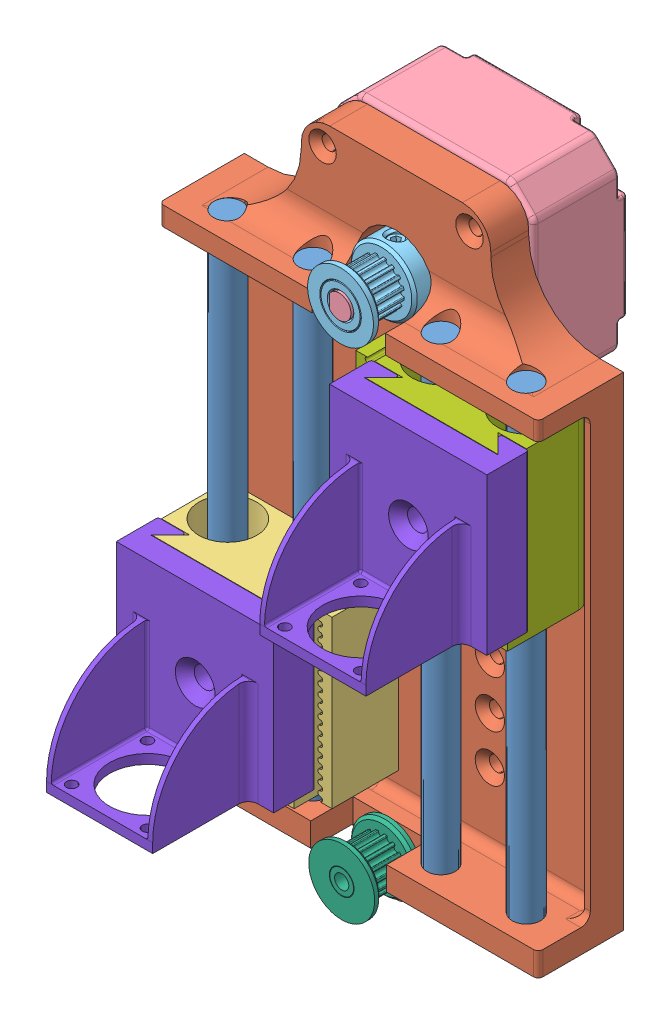
SolidWorks assembly Сборка1, configuration По умолчанию. Lengths in mm.
Overall size (80 136.39 68.13).
12 component instances, 8 part files, 26 mates.
Components (placement in the parent):
- 6x100-1: 6x100 [По умолчанию] at (56.1311 0.0146 -7.1072) x (1 0 0) z (0 1 0) size (6 6 100)
- main-1: main [По умолчанию] at (87.6311 49.0146 -19.1072) size (80 135.39 18)
- 6x100-2: 6x100 [По умолчанию] at (74.1311 0.0146 -7.1072) x (1 0 0) z (0 1 0) size (6 6 100)
- 6x100-3: 6x100 [По умолчанию] at (101.1311 0.0146 -7.1072) x (1 0 0) z (0 1 0) size (6 6 100)
- 6x100-4: 6x100 [По умолчанию] at (119.1311 0.0146 -7.1072) x (0.999887 0 -0.01506) z (0 1 0) size (6 6 100)
- head-1: head [По умолчанию] at (65.1311 25.9903 -14.1072) size (36 35 18)
- Short Body Nema 17 Bipolar Step Motor-1: Short Body Nema 17 Bipolar Step Motor [По умолчанию] at (66.6311 81.0146 -39.1072) size (42 42 40)
- GT2_16T-1: GT2_16T [Конфигурация1] at (87.6311 102.0146 -14.8955) x (0 0 1) z (-0.998524 -0.054321 0) size (15.5 13.9 13.9)
- GT2 16 Teeth Free Pulley-1: GT2 16 Teeth Free Pulley [По умолчанию] at (87.6311 -3.3706 -14.943) x (0 0 1) z (-0.999696 -0.02467 0) size (9.9 13.9 13.9)
- head2-1: head2 [По умолчанию] at (110.1311 77.2667 -14.1072) x (-1 0 0) z (0 0 1) size (36 35 18)
- nema8_holder-1: nema8_holder [По умолчанию] at (65.2175 10.4903 0.0436) x (1 0 0) z (0 1 0) size (33.2 29.03 33)
- nema8_holder-2: nema8_holder [По умолчанию] at (110.2175 61.7667 0.0436) x (1 0 0) z (0 1 0) size (33.2 29.03 33)
Mates (geometry in assembly coordinates):
- Концентричный4: concentric anti-aligned: cylinder of 6x100-1 through (56.1311 100.0146 -7.1072) axis (0 -1 0) radius 3; cylinder of main-1 through (56.1311 0.0146 -7.1072) axis (0 1 0) radius 2.95
- Совпадение1: coincident aligned: plane of 6x100-1 through (56.1311 100.0146 -7.1072) normal (0 1 0); plane of main-1 through (47.6311 100.0146 -15.1072) normal (0 1 0)
- Концентричный5: concentric anti-aligned: cylinder of main-1 through (74.1311 0.0146 -7.1072) axis (0 1 0) radius 2.95; cylinder of 6x100-2 through (74.1311 100.0146 -7.1072) axis (0 -1 0) radius 3
- Совпадение2: coincident aligned: plane of main-1 through (47.6311 100.0146 -15.1072) normal (0 1 0); plane of 6x100-2 through (74.1311 100.0146 -7.1072) normal (0 1 0)
- Концентричный6: concentric anti-aligned: cylinder of main-1 through (101.1311 0.0146 -7.1072) axis (0 1 0) radius 2.95; cylinder of 6x100-3 through (101.1311 100.0146 -7.1072) axis (0 -1 0) radius 3
- Совпадение3: coincident aligned: plane of main-1 through (47.6311 100.0146 -15.1072) normal (0 1 0); plane of 6x100-3 through (101.1311 100.0146 -7.1072) normal (0 1 0)
- Концентричный7: concentric anti-aligned: cylinder of main-1 through (119.1311 0.0146 -7.1072) axis (0 1 0) radius 2.95; cylinder of 6x100-4 through (119.1311 100.0146 -7.1072) axis (0 -1 0) radius 3
- Совпадение5: coincident anti-aligned: plane of main-1 through (119.1311 0.0146 -7.1072) normal (0 1 0); plane of 6x100-4 through (119.1311 0.0146 -7.1072) normal (0 -1 0)
- Концентричный8: concentric anti-aligned: cylinder of 6x100-1 through (56.1311 100.0146 -7.1072) axis (0 -1 0) radius 3; cylinder of head-1 through (56.1311 8.4893 -7.1072) axis (0 1 0) radius 6.1
- Параллельность1: parallel anti-aligned: cylinder of 6x100-2 through (74.1311 100.0146 -7.1072) axis (0 -1 0) radius 3; cylinder of head-1 through (74.1311 8.4893 -7.1072) axis (0 1 0) radius 6.1
- Концентричный10: concentric anti-aligned: cylinder of 6x100-2 through (74.1311 100.0146 -7.1072) axis (0 -1 0) radius 3; cylinder of head-1 through (74.1311 8.4893 -7.1072) axis (0 1 0) radius 6.1
- Концентричный11: concentric anti-aligned: cylinder of 6x100-3 through (101.1311 100.0146 -7.1072) axis (0 -1 0) radius 3; cylinder of head-2 through (101.1311 60.8768 -7.1072) axis (0 1 0) radius 6
- Концентричный12: concentric anti-aligned: cylinder of 6x100-4 through (119.1311 100.0146 -7.1072) axis (0 -1 0) radius 3; cylinder of head-2 through (119.1311 60.8768 -7.1072) axis (0 1 0) radius 6
- Концентричный13: concentric aligned: cylinder of main-1 through (87.6311 102.0146 -1.1062) axis (0 0 -1) radius 8; cylinder of Short Body Nema 17 Bipolar Step Motor-1 through (87.6311 102.0146 -19.1072) axis (0 0 -1) radius 11
- Концентричный14: concentric aligned: cylinder of main-1 through (103.1311 117.5146 -1.1062) axis (0 0 -1) radius 1.5; cylinder of Short Body Nema 17 Bipolar Step Motor-1 through (103.1311 117.5146 -20.3572) axis (0 0 -1) radius 1.23
- Совпадение6: coincident anti-aligned: plane of main-1 through (87.6311 49.0146 -19.1072) normal (0 0 -1); plane of Short Body Nema 17 Bipolar Step Motor-1 through (87.6311 102.0146 -19.1072) normal (0 0 1)
- Концентричный15: concentric anti-aligned: cylinder of Short Body Nema 17 Bipolar Step Motor-1 through (87.6311 102.0146 -19.1072) axis (0 0 -1) radius 2.5; cylinder of GT2_16T-1 through (87.6311 102.0146 -14.8955) axis (0 0 1) radius 2.5
- Концентричный17: concentric anti-aligned: cylinder of main-1 through (87.6311 -3.3706 -19.1082) axis (0 0 1) radius 1.5; cylinder of GT2 16 Teeth Free Pulley-1 through (87.6311 -3.3706 -9.543) axis (0 0 -1) radius 1.5
- Концентричный18: concentric aligned: cylinder of 6x100-3 through (101.1311 100.0146 -7.1072) axis (0 -1 0) radius 3; cylinder of head2-1 through (101.1311 94.7677 -7.1072) axis (0 -1 0) radius 6.1
- Концентричный19: concentric aligned: cylinder of 6x100-4 through (119.1311 100.0146 -7.1072) axis (0 -1 0) radius 3; cylinder of head2-1 through (119.1311 94.7677 -7.1072) axis (0 -1 0) radius 6.1
- Совпадение7: coincident anti-aligned: plane of head-1 through (79.1311 10.4903 3.8928) normal (0.707107 0 -0.707107); plane of nema8_holder-1 through (79.2311 43.4903 3.9928) normal (-0.707107 0 0.707107)
- Совпадение8: coincident anti-aligned: plane of head-1 through (51.1311 10.4903 3.8928) normal (-0.707107 0 -0.707107); plane of nema8_holder-1 through (51.0311 43.4903 3.9928) normal (0.707107 0 0.707107)
- Совпадение9: coincident aligned: plane of head-1 through (49.1311 43.4903 -0.1072) normal (0 1 0); plane of nema8_holder-1 through (76.4382 43.4903 0.4928) normal (0 1 0)
- Совпадение10: coincident anti-aligned: plane of head2-1 through (96.1311 61.7667 3.8928) normal (-0.707107 0 -0.707107); plane of nema8_holder-2 through (96.0311 94.7667 3.9928) normal (0.707107 0 0.707107)
- Совпадение11: coincident anti-aligned: plane of head2-1 through (124.1311 61.7667 3.8928) normal (0.707107 0 -0.707107); plane of nema8_holder-2 through (124.2311 94.7667 3.9928) normal (-0.707107 0 0.707107)
- Совпадение12: coincident aligned: plane of head2-1 through (126.1311 94.7667 -0.1072) normal (0 1 0); plane of nema8_holder-2 through (121.4382 94.7667 0.4928) normal (0 1 0)
